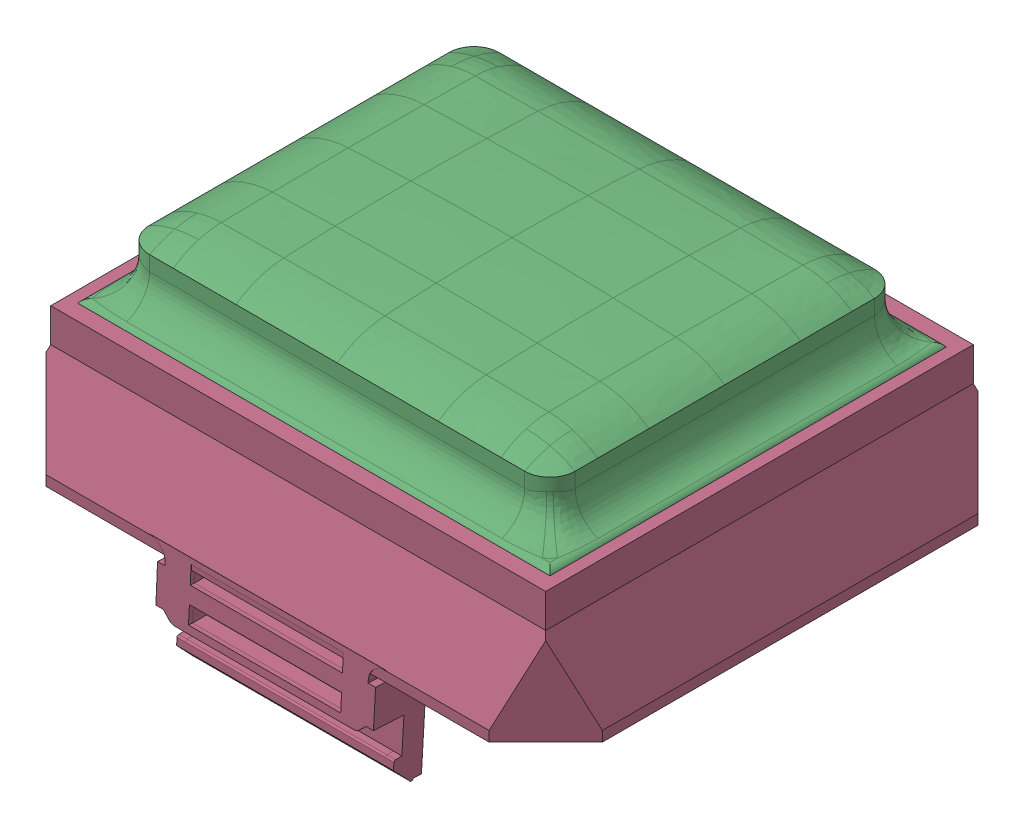
SolidWorks assembly Coord, configuration 默认. Lengths in mm.
Overall size (33 18.27 29.5).
5 component instances, 5 part files, 12 mates.
Components (placement in the parent):
- Coordlensall-1: Coordlensall [默认] at origin size (28.33 2.18 23.83)
- CoordInsideSkin1 (1)-1: CoordInsideSkin1 (1) [默认] at (0.0001 0 0.2499) size (23.8 5.48 19.29)
- CoordTopskin-1: CoordTopskin [默认] at (0.0001 2 0.2499) size (28.02 6.25 23.52)
- NewContiSupportBase-2: NewContiSupportBase [默认] at origin size (33 14.02 29.5)
- CoordinateMarker-1: CoordinateMarker [默认] at (-1.2748 23.7 0.6861) x (1 0 0) z (0 -1 0) size (23.6 17.6 1.5)
Mates (geometry in assembly coordinates):
- 同心2: concentric anti-aligned: cylinder of CoordInsideSkin1 (1)-1 through (10.8751 17.7531 8.6249) axis (0 1 0) radius 0.7; cylinder of Board3Con1612611OriginalSkin_TOP-1 through (10.8751 24 8.6249) axis (0 -1 0) radius 0.7
- 同心3: concentric anti-aligned: cylinder of CoordInsideSkin1 (1)-1 through (10.8751 17.7531 -9.1251) axis (0 1 0) radius 0.7; cylinder of Board3Con1612611OriginalSkin_TOP-1 through (10.8751 24 -9.1251) axis (0 -1 0) radius 0.7
- 重合4: coincident aligned: plane of CoordInsideSkin1 (1)-1 through (10.8751 19 -9.1251) normal (0 -1 0); plane of Board3Con1612611OriginalSkin_TOP-1 through (0.0001 19 0.2499) normal (0 -1 0)
- 重合6: coordinate: point of NewContiSupportBase-2
- 重合7: coincident anti-aligned: plane of lensall-1 through (13.75 19 -11.5) normal (0.939693 0.34202 0); plane of NewContiSupportBase-2 through (13.75 19 12.7803) normal (-0.939693 -0.34202 0)
- 同心5: concentric aligned: cylinder of lensall-1 through (13.3294 18.6938 -11.0794) axis (-0.323616 0.889126 0.323616) radius 0.5; cylinder of NewContiSupportBase-2 through (10.7866 25.6801 -8.5366) axis (-0.323616 0.889126 0.323616) radius 0.5
- 重合8: coincident anti-aligned: plane of lensall-1 through (0 18 0) normal (0 -1 0); plane of NewContiSupportBase-2 through (0 18 0) normal (0 1 0)
- 重合9: coincident anti-aligned: plane of lensall-1 through (0 19 0) normal (0 1 0); plane of Board3Con1612611OriginalSkin_TOP-1 through (0.0001 19 0.2499) normal (0 -1 0)
- 重合10: coincident anti-aligned: plane of Board3Con1612611OriginalSkin_TOP-1 through (0.0001 19 11.7499) normal (0 0 1); plane of NewContiSupportBase-2 through (-13.5999 21 11.7499) normal (0 0 -1)
- 重合11: coincident anti-aligned: plane of Board3Con1612611OriginalSkin_TOP-1 through (14.0001 19 0.2499) normal (1 0 0); plane of NewContiSupportBase-2 through (14.0001 21 11.7499) normal (-1 0 0)
- 宽度1: width aligned: plane of CoordInsideSkin1 (1)-1 through (11.5751 17.7531 -9.1251) normal (1 0 0); plane of CoordInsideSkin1 (1)-1 through (-12.0749 17.7531 -9.1251) normal (-1 0 0); plane of CoordinateMarker-1 through (11.5501 22.95 -8.2501) normal (1 0 0); plane of CoordinateMarker-1 through (-12.0499 22.95 -8.2501) normal (-1 0 0)
- 重合12: coincident aligned: circle of CoordInsideSkin1 (1)-1; circle of CoordinateMarker-1
